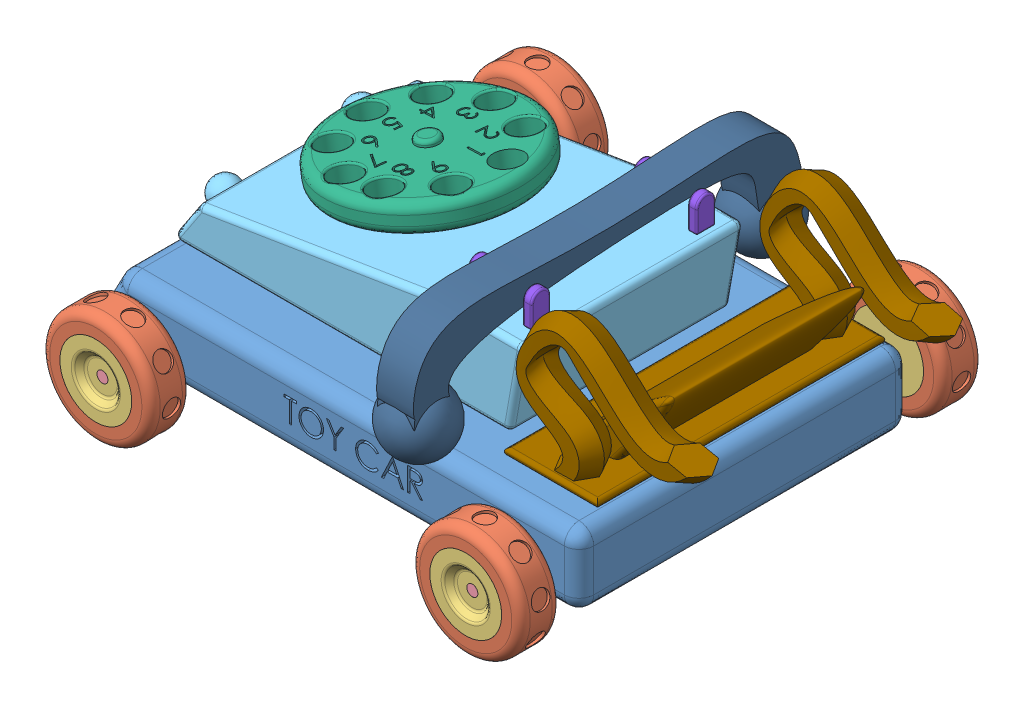
SolidWorks assembly Final_Toy_Assembly, configuration Default. Lengths in mm.
Overall size (307.61 149.26 251.2).
26 component instances, 10 part files, 27 mates.
Components (placement in the parent):
- Base-1: Base [Default] at (114.2561 112.6645 204.1051) size (265.42 39 180)
- Wheel_Axle_Assembly-1: Wheel_Axle_Assembly [Default] at (-2.5771 97.6139 43.1995) size (78.41 78.41 251.2)
  - Wheel_Assembly-1: Wheel_Assembly [Default] at (17.2762 1.443 -10.0968) size (60 60 22)
    - Wheel_External-1: Wheel_External [Default] at (-0.9064 32.1198 46.8024) size (60 60 22)
    - Wheel_Ring-1: Wheel_Ring [Default] at (-0.9064 32.1198 57.8024) size (39 39 22)
  - Wheel_Axle-1: Wheel_Axle [Default] at (16.3698 33.5629 40.3056) x (0 0 1) z (-1 0 0) size (244 6 6)
  - Wheel_Assembly-2: Wheel_Assembly [Default] at (27.836 3.5457 334.7079) x (-0.923728 -0.383049 0) z (0 0 -1) size (60 60 22)
    - Wheel_External-1: Wheel_External [Default] at (-0.9064 32.1198 46.8024) size (60 60 22)
    - Wheel_Ring-1: Wheel_Ring [Default] at (-0.9064 32.1198 57.8024) size (39 39 22)
- Wheel_Axle_Assembly-2: Wheel_Axle_Assembly [Default] at (248.9523 146.0949 43.1995) x (-0.760937 0.648826 0) z (0 0 1) size (78.41 78.41 251.2)
  - Wheel_Assembly-1: Wheel_Assembly [Default] at (17.2762 1.443 -10.0968) size (60 60 22)
    - Wheel_External-1: Wheel_External [Default] at (-0.9064 32.1198 46.8024) size (60 60 22)
    - Wheel_Ring-1: Wheel_Ring [Default] at (-0.9064 32.1198 57.8024) size (39 39 22)
  - Wheel_Axle-1: Wheel_Axle [Default] at (16.3698 33.5629 40.3056) x (0 0 1) z (-1 0 0) size (244 6 6)
  - Wheel_Assembly-2: Wheel_Assembly [Default] at (27.836 3.5457 334.7079) x (-0.923728 -0.383049 0) z (0 0 -1) size (60 60 22)
    - Wheel_External-1: Wheel_External [Default] at (-0.9064 32.1198 46.8024) size (60 60 22)
    - Wheel_Ring-1: Wheel_Ring [Default] at (-0.9064 32.1198 57.8024) size (39 39 22)
- Upper_Base-1: Upper_Base [Default] at (71.8928 151.6645 264.1051) x (-1 0 0) z (0 0 -1) size (195.2 44.11 120)
- Rotary_Dial-1: Rotary_Dial [Default] at (67.2134 207.5558 204.1051) x (0.135772 0.022085 -0.990494) z (-0.977645 -0.159023 -0.137556) size (100 23 100)
- Rotary_Dial_Upper_Base_Axle-1: Rotary_Dial_Upper_Base_Axle [Default] at (67.2134 207.5558 204.1051) x (-0.831779 -0.135296 -0.538367) z (-0.531383 -0.086434 0.84271) size (5 26 5)
- Phone_Holder-1: Phone_Holder [Default] at (168.5731 195.7721 155.3157) x (0 0 -1) z (1 0 0) size (10.34 17.17 5)
- Phone_Holder-3: Phone_Holder [Default] at (143.5731 195.7721 252.8944) x (0 0 1) z (-1 0 0) size (10.34 17.17 5)
- Phone_Holder-4: Phone_Holder [Default] at (138.5731 195.7721 155.3157) x (0 0 -1) z (1 0 0) size (10.34 17.17 5)
- Phone_Holder-5: Phone_Holder [Default] at (173.5731 195.7721 252.8944) x (0 0 1) z (-1 0 0) size (10.34 17.17 5)
- Back_Trunk-1: Back_Trunk [Default] at (205.9202 151.6645 198.0195) x (0 0 -1) z (1 0 0) size (155.99 73.5 101.47)
- Phone-1: Phone [Default] at (166.9508 173.1911 203.8183) x (0 0 1) z (-1 0 0) size (221.5 72.96 36.47)
Mates (geometry in assembly coordinates):
- Concentric1: concentric anti-aligned: cylinder of Base-1 through (13.7927 131.1768 114.1051) axis (0 0 1) radius 3; cylinder of Wheel_Axle_Assembly-1/Wheel_Axle-1 through (13.7927 131.1768 327.5051) axis (0 0 -1) radius 3
- Distance1: distance = 15 mm anti-aligned: plane of Wheel_Axle_Assembly-1/Wheel_Assembly-2/Wheel_Ring-1 through (13.7927 131.1768 309.1051) normal (0 0 -1); plane of Base-1 through (-10.7439 151.6645 294.1051) normal (0 0 1)
- Concentric3: concentric anti-aligned: cylinder of Base-1 through (214.7194 131.1768 114.1051) axis (0 0 1) radius 3; cylinder of Wheel_Axle_Assembly-2/Wheel_Axle-1 through (214.7194 131.1768 327.5051) axis (0 0 -1) radius 3
- Distance3: distance = 15 mm anti-aligned: plane of Wheel_Axle_Assembly-2/Wheel_Assembly-2/Wheel_Ring-1 through (214.7194 131.1768 309.1051) normal (0 0 -1); plane of Base-1 through (-10.7439 151.6645 294.1051) normal (0 0 1)
- Coincident3: coincident anti-aligned: plane of Base-1 through (114.2561 151.6645 204.1051) normal (0 1 0); plane of Upper_Base-1 through (141.2961 151.6645 144.1051) normal (0 -1 0)
- Distance4: distance = 30 mm aligned: plane of Base-1 through (-10.7439 151.6645 114.1051) normal (0 0 -1); plane of Upper_Base-1 through (71.8928 151.6645 144.1051) normal (0 0 -1)
- Distance8: distance = 71 mm: point of Upper_Base-1; line of Base-1 through (231.2561 151.6645 286.1051) axis (0 0 -1)
- Coincident4: coincident anti-aligned: plane of Upper_Base-1 through (71.3876 181.8931 204.1051) normal (-0.160549 0.987028 0); plane of Rotary_Dial_Upper_Base_Axle-1 through (71.3876 181.8931 204.1051) normal (0.160549 -0.987028 0)
- Concentric4: concentric aligned: cylinder of Upper_Base-1 through (71.3876 181.8931 204.1051) axis (-0.160549 0.987028 0) radius 2.5; cylinder of Rotary_Dial_Upper_Base_Axle-1 through (71.3876 181.8931 204.1051) axis (-0.160549 0.987028 0) radius 2.5
- Coincident5: coincident anti-aligned: plane of Rotary_Dial-1 through (67.2134 207.5558 204.1051) normal (0.160549 -0.987028 0); plane of Rotary_Dial_Upper_Base_Axle-1 through (67.2134 207.5558 204.1051) normal (-0.160549 0.987028 0)
- Concentric6: concentric anti-aligned: cylinder of Rotary_Dial-1 through (67.1409 208.0015 204.1051) axis (0.160549 -0.987028 0) radius 2.5; cylinder of Rotary_Dial_Upper_Base_Axle-1 through (71.3876 181.8931 204.1051) axis (-0.160549 0.987028 0) radius 2.5
- Coincident6: coincident anti-aligned: plane of Upper_Base-1 through (179.1939 195.7721 144.1051) normal (0 1 0); plane of Phone_Holder-5 through (168.5731 195.7721 254.1051) normal (0 -1 0)
- Distance9: distance = 10 mm aligned: plane of Phone_Holder-5 through (168.5731 207.7721 254.1051) normal (0 0 1); plane of Upper_Base-1 through (71.8928 151.6645 264.1051) normal (0 0 1)
- Distance10: distance = 5 mm: line of Upper_Base-1 through (178.5731 192.2512 147.1051) axis (0 0 1); plane of Phone_Holder-5 through (173.5731 207.7721 248.9338) normal (1 0 0)
- Coincident9: coincident anti-aligned: plane of Upper_Base-1 through (179.1939 195.7721 144.1051) normal (0 1 0); plane of Phone_Holder-3 through (138.5731 195.7721 254.1051) normal (0 -1 0)
- Distance11: distance = 10 mm aligned: plane of Phone_Holder-3 through (138.5731 207.7721 254.1051) normal (0 0 1); plane of Upper_Base-1 through (71.8928 151.6645 264.1051) normal (0 0 1)
- Distance12: distance = 35 mm: plane of Phone_Holder-3 through (143.5731 207.7721 248.9338) normal (1 0 0); line of Upper_Base-1 through (178.5731 192.2512 147.1051) axis (0 0 1)
- Coincident12: coincident anti-aligned: plane of Upper_Base-1 through (179.1939 195.7721 144.1051) normal (0 1 0); plane of Phone_Holder-1 through (173.5731 195.7721 154.1051) normal (0 -1 0)
- Distance13: distance = 10 mm aligned: plane of Phone_Holder-1 through (173.5731 207.7721 154.1051) normal (0 0 -1); plane of Upper_Base-1 through (71.8928 151.6645 144.1051) normal (0 0 -1)
- Distance14: distance = 5 mm: plane of Phone_Holder-1 through (173.5731 207.7721 159.2764) normal (1 0 0); line of Upper_Base-1 through (178.5731 192.2512 147.1051) axis (0 0 1)
- Coincident15: coincident anti-aligned: plane of Upper_Base-1 through (179.1939 195.7721 144.1051) normal (0 1 0); plane of Phone_Holder-4 through (143.5731 195.7721 154.1051) normal (0 -1 0)
- Distance15: distance = 10 mm aligned: plane of Phone_Holder-4 through (143.5731 207.7721 154.1051) normal (0 0 -1); plane of Upper_Base-1 through (71.8928 151.6645 144.1051) normal (0 0 -1)
- Distance16: distance = 35 mm: plane of Phone_Holder-4 through (143.5731 207.7721 159.2764) normal (1 0 0); line of Upper_Base-1 through (178.5731 192.2512 147.1051) axis (0 0 1)
- Coincident16: coincident anti-aligned: plane of Base-1 through (114.2561 151.6645 204.1051) normal (0 1 0); plane of Back_Trunk-1 through (205.9202 151.6645 198.0195) normal (0 -1 0)
- Parallel3: parallel aligned: line of Base-1 through (231.2561 151.6645 286.1051) axis (0 0 -1); line of Back_Trunk-1 through (231.2561 153.6645 276.0146) axis (0 0 -1)
- Distance18: distance = 2 mm: line of Back_Trunk-1 through (231.2561 153.6645 276.0146) axis (0 0 -1); line of Base-1 through (231.2561 151.6645 286.1051) axis (0 0 -1)
- Parallel4: parallel anti-aligned: plane of Base-1 through (114.2561 112.6645 204.1051) normal (1 0 0); plane of Phone-1 through (166.9508 173.1911 203.8183) normal (-1 0 0)
